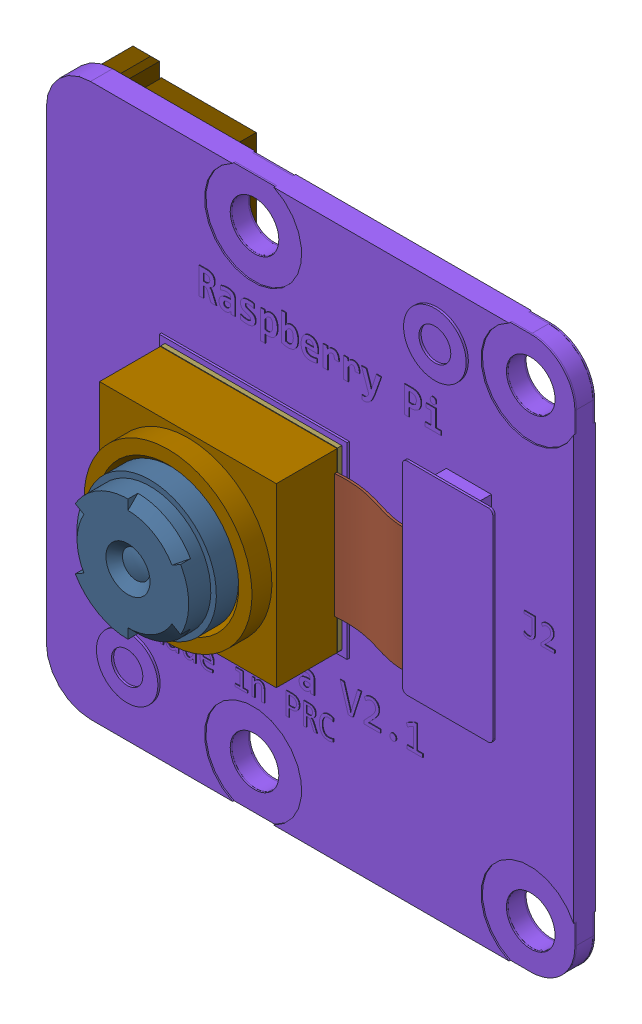
SolidWorks assembly RspCameraMia, configuration Défaut. Lengths in mm.
Overall size (23.86 25 9.96).
41 component instances, 22 part files, 0 mates.
Components (placement in the parent):
- RspCameraMia.stp-1: RspCameraMia.stp [Défaut] at origin size (23.86 25 9.96)
  - 70521906.stp-1: 70521906.stp [Défaut] at (1.7167 0.8597 0.0159) size (2 2.1 0.95)
    - 70521906_01.stp-1: 70521906_01.stp [Défaut] at origin size (0.25 0.55 0.75)
    - 70521906_02.stp-1: 70521906_02.stp [Défaut] at origin size (0.25 0.55 0.75)
    - 70521906_03.stp-1: 70521906_03.stp [Défaut] at origin size (2 1.25 0.9)
    - 70521906_04.stp-1: 70521906_04.stp [Défaut] at origin size (0.25 0.55 0.75)
    - 70521906_05.stp-1: 70521906_05.stp [Défaut] at origin size (0.25 0.55 0.75)
    - 70521906_06.stp-1: 70521906_06.stp [Défaut] at origin size (0.25 0.55 0.75)
    - 70521906_07.stp-1: 70521906_07.stp [Défaut] at origin size (0.25 0.55 0.75)
  - PicameraPCB.stp-1: PicameraPCB.stp [Défaut] at (0.2393 -0.0199 0) x (-1 0 0) z (0 0 1) size (23.86 25 2.2)
  - OVA5647_Housing.stp-1: OVA5647_Housing.stp [Défaut] at (-2.4078 0.0859 1) x (1 0 0) z (0 -1 0) size (8 3.95 8)
  - OVA5647_Lens_FOV.stp-1: OVA5647_Lens_FOV.stp [Défaut] at (-2.4087 0.0921 5.963) x (1 0 0) z (0 -1 0) size (6 3.35 6)
  - ribbon_cam.stp-1: ribbon_cam.stp [Défaut] at (-2.4804 0.3633 1.4162) x (0 1 0) z (1 0 0) size (5.6 0.69 4.76)
  - CCD.stp-1: CCD.stp [Défaut] at (-2.0757 0.287 1.296) x (1 0 0) z (0 -1 0) size (8.01 0.69 8.01)
  - CAPC-0805-T0.75-BN.stp-1: CAPC-0805-T0.75-BN.stp [Défaut] at (4.562 5.9833 -0.0026) x (0 -1 0) z (0 0 -1) size (2.1 1.35 0.75)
  - CAPC-0805-T0.75-BN.stp-2: CAPC-0805-T0.75-BN.stp [Défaut] at (2.0233 10.2705 -0.0026) x (0 -1 0) z (0 0 -1) size (2.1 1.35 0.75)
  - CAPC-0402-T0.55-BN.stp-1: CAPC-0402-T0.55-BN.stp [Défaut] at (-2.9562 6.224 -0.2572) x (-1 0 0) z (0 -1 0) size (1.05 0.55 0.55)
  - CAPC-0402-T0.55-BN.stp-2: CAPC-0402-T0.55-BN.stp [Défaut] at (-2.9504 5.2898 -0.2691) x (-1 0 0) z (0 -1 0) size (1.05 0.55 0.55)
  - CAPC-0402-T0.55-BN.stp-3: CAPC-0402-T0.55-BN.stp [Défaut] at (4.5768 -5.1833 -0.2811) x (-1 0 0) z (0 -1 0) size (1.05 0.55 0.55)
  - CAPC-0402-T0.55-BN.stp-4: CAPC-0402-T0.55-BN.stp [Défaut] at (2.5547 -5.1368 -0.2811) x (-1 0 0) z (0 -1 0) size (1.05 0.55 0.55)
  - CAPC-0402-T0.55-BN.stp-5: CAPC-0402-T0.55-BN.stp [Défaut] at (2.6129 -9.93 -0.293) x (-1 0 0) z (0 -1 0) size (1.05 0.55 0.55)
  - CAPC-0402-T0.55-BN.stp-6: CAPC-0402-T0.55-BN.stp [Défaut] at (4.7286 -9.9294 -0.293) x (-1 0 0) z (0 -1 0) size (1.05 0.55 0.55)
  - CAPC-0402-T0.55-BN.stp-7: CAPC-0402-T0.55-BN.stp [Défaut] at (8.4068 -3.8793 -0.2811) x (-1 0 0) z (0 -1 0) size (1.05 0.55 0.55)
  - CAPC-0402-T0.55-BN.stp-8: CAPC-0402-T0.55-BN.stp [Défaut] at (9.0088 0.0217 -0.2796) x (0 1 0) z (-1 0 0) size (1.05 0.55 0.55)
  - CAPC-0402-T0.55-BN.stp-9: CAPC-0402-T0.55-BN.stp [Défaut] at (10.4284 2.6731 -0.3022) x (0 1 0) z (-1 0 0) size (1.05 0.55 0.55)
  - CAPC-0402-T0.55-BN.stp-10: CAPC-0402-T0.55-BN.stp [Défaut] at (8.2321 1.3259 -0.2838) x (1 0 0) z (0 1 0) size (1.05 0.55 0.55)
  - RESC-0402.stp-1: RESC-0402.stp [Défaut] at (3.7919 0.0148 -0.0114) x (1 0 0) z (0 0 -1) size (1.05 0.55 0.4)
  - RESC-0402.stp-2: RESC-0402.stp [Défaut] at (4.1232 2.6296 -0.0028) x (0 -1 0) z (0 0 -1) size (1.05 0.55 0.4)
  - RESC-0402.stp-3: RESC-0402.stp [Défaut] at (10.5883 -6.2795 -0.0019) x (0 1 0) z (0 0 -1) size (1.05 0.55 0.4)
  - RESC-0603.stp-1: RESC-0603.stp [Défaut] at (-2.6191 7.0617 -0.0121) x (1 0 0) z (0 0 -1) size (1.7 0.9 0.55)
  - RESC-0603.stp-2: RESC-0603.stp [Défaut] at (-3.4466 3.0018 -0.0048) x (0 -1 0) z (0 0 -1) size (1.7 0.9 0.55)
  - RESC-1210.stp-1: RESC-1210.stp [Défaut] at (2.2265 5.9002 -0.0068) x (0 -1 0) z (0 0 -1) size (3.3 2.7 0.6)
  - c-1-1734248-5-e-raspberry_display.stp-1: c-1-1734248-5-e-raspberry_display.stp [Défaut] at (-10.6651 0.0449 -1.5) x (0 -1 0) z (-1 0 0) size (22.4 3.22 5.68)
  - SOT23-5.stp-1: SOT23-5.stp [Défaut] at (4.2989 9.8879 0.5457) x (0 -1 0) z (0 0 -1) size (2.84 3.01 1.19)
  - SOT23-5.stp-2: SOT23-5.stp [Défaut] at (3.5194 -3.2493 0.04) x (-1 0 0) z (0 0 -1) size (2.84 3.01 1.19)
  - SOT23-5.stp-3: SOT23-5.stp [Défaut] at (3.5816 -8.055 0.0206) x (-1 0 0) z (0 0 -1) size (2.84 3.01 1.19)
  - KX7 SMD Quartz Crystal Resonator 3.2x2.5mm.stp-1: KX7 SMD Quartz Crystal Resonator 3.2x2.5mm.stp [Défaut] at (9.9746 -4.9221 0.0339) x (-1 0 0) z (0 -1 0) size (3.2 0.6 2.5)
  - c6aaa.stp-1: c6aaa.stp [Défaut] at (0.0643 0.0942 0) x (1 0 0) z (0 0 -1) size (2 2.99 0.6)
  - 4pin_smd.stp-1: 4pin_smd.stp [Défaut] at (0.027 0.0676 0) x (1 0 0) z (0 0 -1) size (1.29 1 0.47)
  - 4pin_smd.stp-2: 4pin_smd.stp [Défaut] at (-0.0093 -6.0092 -0.0198) x (1 0 0) z (0 0 -1) size (1.29 1 0.47)
  - 4pin_smd.stp-3: 4pin_smd.stp [Défaut] at (0.0326 -3.0068 -0.0235) x (1 0 0) z (0 0 -1) size (1.29 1 0.47)
